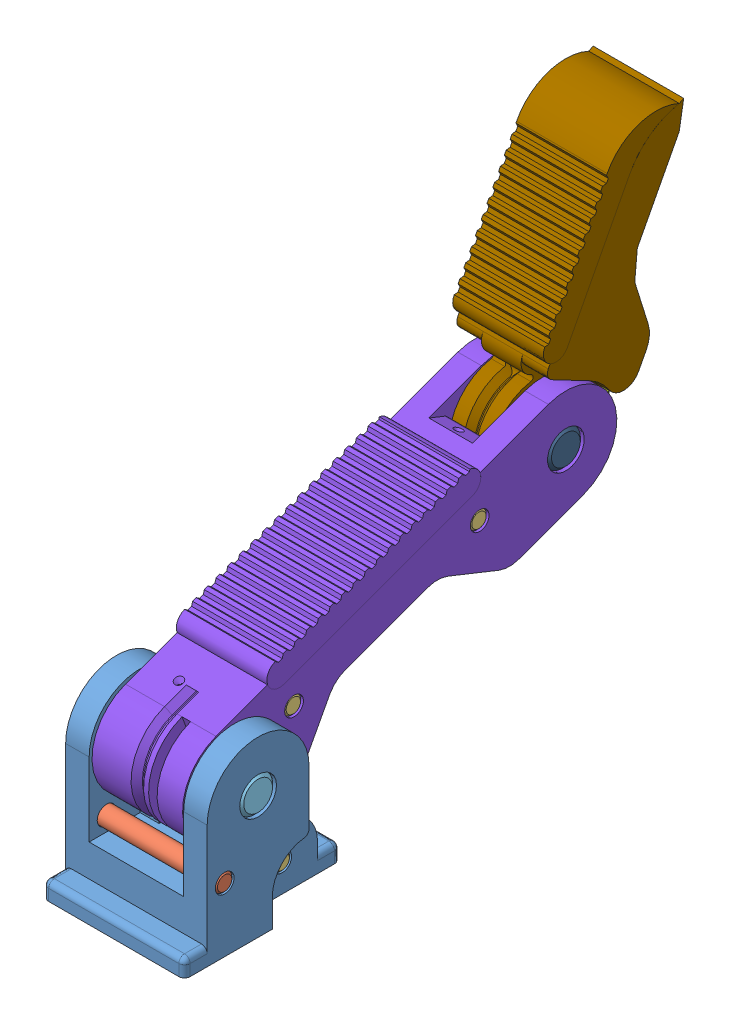
SolidWorks assembly block_finger_pp_t, configuration Default. Lengths in mm.
Overall size (25.4 90.81 104.27).
16 component instances, 10 part files, 30 mates.
Components (placement in the parent):
- c1_t-1: c1_t [Default] at origin size (25 30.67 32)
- 98381A475 D1-8 L1-1: 98381A475 D1-8 L1 [98381A475] at (-0.2 11.2575 -8.8732) size (25.4 3.17 3.17)
- 98381A472 D1-8 L5-8-3: 98381A472 D1-8 L5-8 [98381A472] at (0.0625 4.925 -23.535) size (15.88 3.17 3.17)
- 3434T31 - nylon pulley-1: 3434T31 - nylon pulley [Default] at (-0.15 4.925 -23.535) x (0 -1 0) z (0 0 1) size (9.5 2.4 9.5)
- 98381A472 D1-8 L5-8-1: 98381A472 D1-8 L5-8 [98381A472] at (0.0875 27.8748 -25.4819) size (15.88 3.17 3.17)
- 98381A472 D1-8 L5-8-2: 98381A472 D1-8 L5-8 [98381A472] at (0.0875 39.839 -58.2703) size (15.88 3.17 3.17)
- 98381A542 D1-4 L1-1: 98381A542 D1-4 L1 [98381A542] at (-0.2 21.67 -14.7858) size (25.4 6.35 6.35)
- 93365A120 4-40 insert-1: 93365A120 4-40 insert [93365A120] at (0 64.964 -86.0368) x (1 0 0) z (0 0.995964 -0.089757) size (4.37 3.82 4.37)
- 91253A106 4-40 L1-4 countersunk-1: 91253A106 4-40 L1-4 countersunk [91253A106] at (0 64.7736 -88.1494) x (1 0 0) z (0 -0.089757 -0.995964) size (6.48 6.48 6.63)
- finger_pp_t_A-1: finger_pp_t_A [Default] at (0.15 21.67 -14.7858) x (1 0 0) z (0 -0.342783 0.939415) size (16 20.25 80.5)
- finger_pp_t_B-1: finger_pp_t_B [Default] at (0 43.0939 -73.4992) x (1 0 0) z (0 -0.885802 0.464064) size (16 22.88 57.08)
- 98381A539 D1-4 L5-8-1: 98381A539 D1-4 L5-8 [98381A539] at (0.2125 43.0939 -73.4992) size (15.88 6.35 6.35)
- 93365A120 4-40 insert-2: 93365A120 4-40 insert [93365A120] at (0 43.6982 -83.9761) x (1 0 0) z (0 0.885802 -0.464064) size (4.37 3.82 4.37)
- 93365A120 4-40 insert-3: 93365A120 4-40 insert [93365A120] at (0.15 30.6972 -65.7809) x (-0.837169 0.187483 -0.513807) z (-0.546944 -0.286967 0.786449) size (4.37 3.82 4.37)
- 91253A106 4-40 L1-4 countersunk-2: 91253A106 4-40 L1-4 countersunk [91253A106] at (0 42.7139 -85.855) x (1 0 0) z (0 -0.464064 -0.885802) size (6.48 6.48 6.63)
- 91253A106 4-40 L1-4 countersunk-3: 91253A106 4-40 L1-4 countersunk [91253A106] at (0.15 28.7045 -66.5081) x (1 0 0) z (0 -0.939415 -0.342783) size (6.48 6.48 6.63)
Mates (geometry in assembly coordinates):
- Concentric1: concentric: cylinder of c1_t-1 through (-12.5 21.67 -14.7858) axis (1 0 0) radius 3.25; cylinder of 98381A542 D1-4 L1-1 through (-12.9 21.67 -14.7858) axis (1 0 0) radius 3.175
- Coincident1: coincident: plane of c1_t-1 through (12.5 21.67 -14.7858) normal (1 0 0); plane of 98381A542 D1-4 L1-1 through (12.5 21.67 -14.7858) normal (1 0 0)
- Concentric5: concentric: cylinder of c1_t-1 through (-12.5 4.925 -23.535) axis (1 0 0) radius 1.6625; cylinder of 98381A472 D1-8 L5-8-3 through (-7.875 4.925 -23.535) axis (1 0 0) radius 1.5875
- Coincident5: coincident: plane of c1_t-1 through (8 4.925 -23.535) normal (1 0 0); plane of 98381A472 D1-8 L5-8-3 through (8 4.925 -23.535) normal (1 0 0)
- Concentric6: concentric: cylinder of c1_t-1 through (-12.5 11.2575 -8.8732) axis (1 0 0) radius 1.6625; cylinder of 98381A475 D1-8 L1-1 through (-12.9 11.2575 -8.8732) axis (1 0 0) radius 1.5875
- Coincident6: coincident: plane of c1_t-1 through (12.5 21.67 -14.7858) normal (1 0 0); plane of 98381A475 D1-8 L1-1 through (12.5 11.2575 -8.8732) normal (1 0 0)
- Concentric8: concentric: circle of 93365A120 4-40 insert-1; circle of 91253A106 4-40 L1-4 countersunk-1
- Coincident8: coincident: circle of 93365A120 4-40 insert-1; cone of 91253A106 4-40 L1-4 countersunk-1 through (0 64.9628 -86.0497) axis (0 0.089757 0.995964)
- Concentric9: concentric: cylinder of 98381A542 D1-4 L1-1 through (-12.9 21.67 -14.7858) axis (1 0 0) radius 3.175; cylinder of finger_pp_t_A-1 through (-7.85 21.67 -14.7858) axis (1 0 0) radius 3.525
- Distance2: distance = 0.2 mm: plane of finger_pp_t_A-1 through (8.15 21.67 -14.7858) normal (1 0 0); plane of c1_t-1 through (8.35 21.67 -14.7858) normal (-1 0 0)
- Concentric10: concentric: cylinder of 98381A472 D1-8 L5-8-1 through (-7.85 27.8748 -25.4819) axis (1 0 0) radius 1.5875; cylinder of finger_pp_t_A-1 through (-7.85 27.8748 -25.4819) axis (1 0 0) radius 1.6625
- Coincident10: coincident: plane of 98381A472 D1-8 L5-8-1 through (-7.85 27.8748 -25.4819) normal (-1 0 0); plane of finger_pp_t_A-1 through (-7.85 21.67 -14.7858) normal (-1 0 0)
- Concentric11: concentric: cylinder of 98381A472 D1-8 L5-8-2 through (-7.85 39.839 -58.2703) axis (1 0 0) radius 1.5875; cylinder of finger_pp_t_A-1 through (-7.85 39.839 -58.2703) axis (1 0 0) radius 1.6625
- Coincident11: coincident: plane of 98381A472 D1-8 L5-8-2 through (-7.85 39.839 -58.2703) normal (-1 0 0); plane of finger_pp_t_A-1 through (-7.85 21.67 -14.7858) normal (-1 0 0)
- Concentric12: concentric: circle of 93365A120 4-40 insert-1; cylinder of finger_pp_t_B-1 through (0 65.3679 -81.5549) axis (0 -0.089757 -0.995964) radius 1.85
- Coincident12: coincident: plane of 93365A120 4-40 insert-1 through (0 64.964 -86.0368) normal (0 -0.089757 -0.995964); plane of finger_pp_t_B-1 through (-13 67.4539 -86.2612) normal (0 -0.089757 -0.995964)
- Concentric13: concentric: cylinder of finger_pp_t_A-1 through (-7.85 43.0939 -73.4992) axis (1 0 0) radius 3.25; cylinder of finger_pp_t_B-1 through (-8 43.0939 -73.4992) axis (1 0 0) radius 3.525
- Distance3: distance = 0.2 mm: plane of finger_pp_t_B-1 through (-3.5 43.0939 -73.4992) normal (-1 0 0); plane of finger_pp_t_A-1 through (-3.7 43.0939 -73.4992) normal (1 0 0)
- Concentric14: concentric: cylinder of finger_pp_t_B-1 through (-8 43.0939 -73.4992) axis (1 0 0) radius 3.525; cylinder of 98381A539 D1-4 L5-8-1 through (-7.725 43.0939 -73.4992) axis (1 0 0) radius 3.175
- Coincident14: coincident: plane of finger_pp_t_A-1 through (8.15 21.67 -14.7858) normal (1 0 0); plane of 98381A539 D1-4 L5-8-1 through (8.15 43.0939 -73.4992) normal (1 0 0)
- Concentric15: concentric: cylinder of 98381A472 D1-8 L5-8-3 through (-7.875 4.925 -23.535) axis (1 0 0) radius 1.5875; cylinder of 3434T31 - nylon pulley-1 through (-0.15 4.925 -23.535) axis (-1 0 0) radius 1.5
- Distance4: distance = 0.2 mm: plane of 3434T31 - nylon pulley-1 through (-1.35 3.425 -23.535) normal (-1 0 0); plane of c1_t-1 through (-1.55 4.925 -23.535) normal (1 0 0)
- Concentric16: concentric: cylinder of finger_pp_t_A-1 through (0.15 34.9245 -64.2384) axis (0 -0.939415 -0.342783) radius 1.85; circle of 93365A120 4-40 insert-3
- Coincident16: coincident: plane of finger_pp_t_A-1 through (8.15 13.2152 -17.8708) normal (0 -0.939415 -0.342783); plane of 93365A120 4-40 insert-3 through (0.15 30.6972 -65.7809) normal (0 -0.939415 -0.342783)
- Concentric17: concentric: cylinder of finger_pp_t_B-1 through (0 45.5545 -80.4329) axis (0 -0.464064 -0.885802) radius 1.85; circle of 93365A120 4-40 insert-2
- Coincident17: coincident: plane of finger_pp_t_B-1 through (8 38.9173 -81.4714) normal (0 -0.464064 -0.885802); plane of 93365A120 4-40 insert-2 through (0 43.6982 -83.9761) normal (0 -0.464064 -0.885802)
- Concentric18: concentric: circle of finger_pp_t_B-1; circle of 91253A106 4-40 L1-4 countersunk-2
- Coincident18: coincident: circle of 93365A120 4-40 insert-2; cone of 91253A106 4-40 L1-4 countersunk-2 through (0 43.6922 -83.9876) axis (0 0.464064 0.885802)
- Concentric19: concentric: circle of 93365A120 4-40 insert-3; circle of 91253A106 4-40 L1-4 countersunk-3
- Coincident19: coincident: circle of 93365A120 4-40 insert-3; cone of 91253A106 4-40 L1-4 countersunk-3 through (0.15 30.685 -65.7854) axis (0 0.939415 0.342783)
